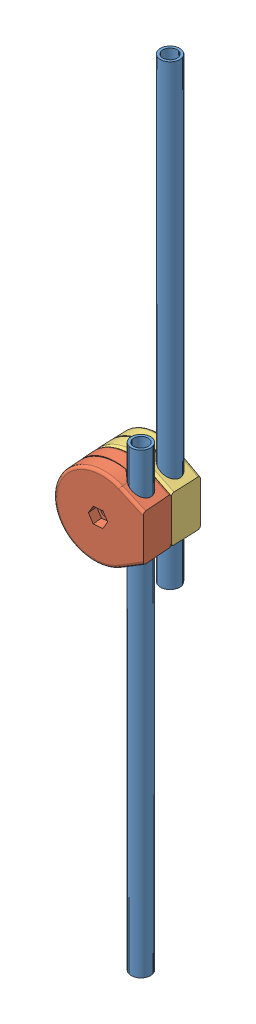
SolidWorks assembly clamshell3, configuration Default. Lengths in mm.
Overall size (93.86 850 76.35).
4 component instances, 3 part files, 8 mates.
Components (placement in the parent):
- pvc-1: pvc [Default] at origin size (21.34 500 21.34)
- shell_left-1: shell_left [Default] at (-28.6368 425 2.1641) x (0.075355 0 0.997157) z (-0.997157 0 0.075355) size (36.37 88.9 89.9)
- shell_right-1: shell_right [Default] at (-30.66 425 -32.6946) x (0.040509 0 0.999179) z (-0.999179 0 0.040509) size (36.37 88.9 89.9)
- pvc-2: pvc [Default] at (-1.965 350 -33.858) x (0.916434 0 0.400185) z (-0.400185 0 0.916434) size (21.34 500 21.34)
Mates (geometry in assembly coordinates):
- Coincident1: coordinate: point of pvc-1
- Concentric1: concentric anti-aligned: cylinder of pvc-1 through (0 500 0) axis (0 -1 0) radius 7.8994; cylinder of shell_left-1 through (0 380.55 0) axis (0 1 0) radius 10.7315
- Distance1: distance = 75 mm: plane of pvc-1 through (0 500 0) normal (0 1 0); cylinder of shell_left-1 through (-30.7035 425 -16.7369) axis (0.092746 0 0.99569) radius 5.5
- Coincident2: coincident anti-aligned: plane of shell_left-1 through (15.4279 450.0859 -17.8814) normal (-0.05794 0 -0.99832); plane of shell_right-1 through (15.4279 450.0859 -17.8814) normal (0.05794 0 0.99832)
- Concentric2: concentric anti-aligned: cylinder of shell_left-1 through (-27.8396 425 21.161) axis (-0.05794 0 -0.99832) radius 5.5; cylinder of shell_right-1 through (-32.0657 425 -51.6562) axis (0.05794 0 0.99832) radius 5.5
- Concentric3: concentric anti-aligned: cylinder of shell_right-1 through (-1.965 380.55 -33.858) axis (0 1 0) radius 10.7315; cylinder of pvc-2 through (-1.965 850 -33.858) axis (0 -1 0) radius 10.668
- Distance2: distance = 75 mm: plane of pvc-2 through (-1.965 350 -33.858) normal (0 -1 0); cylinder of shell_right-1 through (-30.5262 425 -13.6814) axis (-0.023064 0 -0.999734) radius 5.5
- Coincident5: coincident aligned: line of shell_left-1 through (15.4279 403.348 -17.8814) axis (0 1 0); line of shell_right-1 through (15.4279 403.348 -17.8814) axis (0 1 0)
